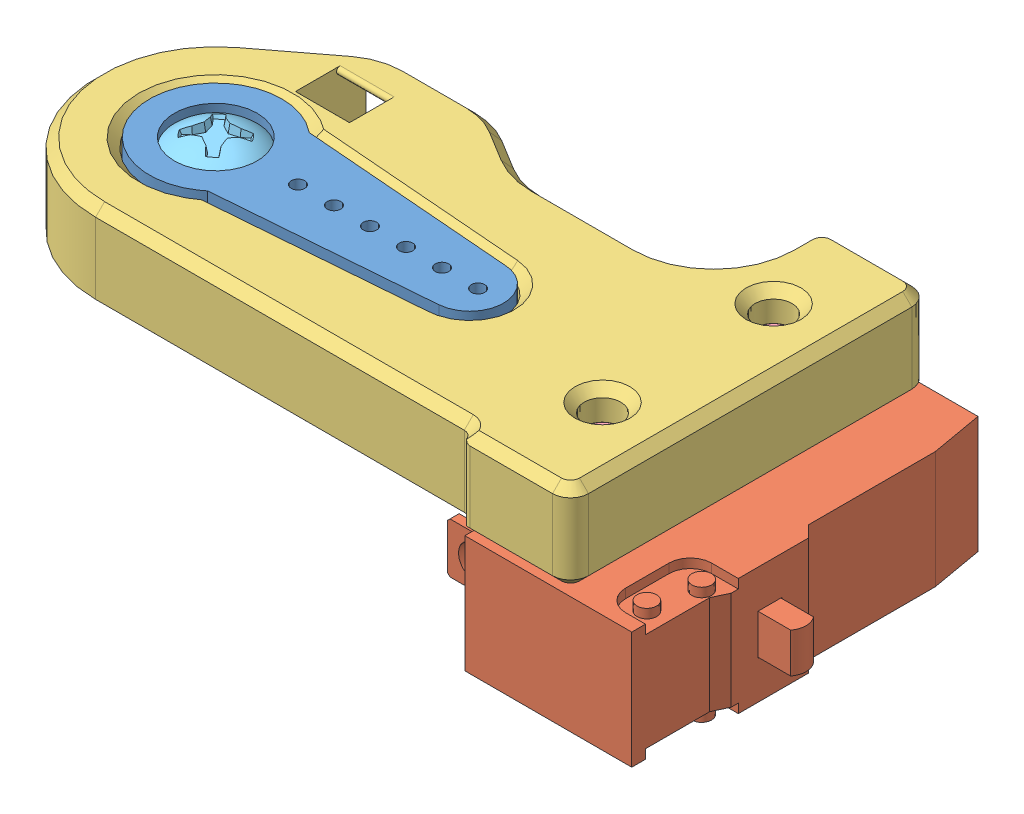
SolidWorks assembly ZProbeAssembly, configuration Default. Lengths in mm.
Overall size (39.46 14.76 19.99).
6 component instances, 5 part files, 12 mates.
Components (placement in the parent):
- Servo Horn-1: Servo Horn [Default] at (34.2536 11.8969 23.9402) size (19.66 4.12 7.35)
- SnapLimitSwitch-1: SnapLimitSwitch [Default] at (22.9628 5.2957 11.2222) x (0.000181 0 -1) z (0 -1 0) size (19.99 14.86 6.5)
- ZProbeArmMirrored-1: ZProbeArmMirrored [Default] at (-0.0025 17.1137 27.8606) x (1 0 0.000181) z (0.000181 0 -1) size (33.66 4.95 19.95)
- M2.5x10HexSocketScrew-1: M2.5x10HexSocketScrew [91292A014] at (25.3259 12.0445 6.4347) x (-0.001575 0 0.999999) z (0 1 0) size (4.5 4.5 13.01)
- M2.5x10HexSocketScrew-2: M2.5x10HexSocketScrew [91292A014] at (25.3241 12.0445 15.9347) x (-0.043466 0 0.999055) z (0 1 0) size (4.5 4.5 13.01)
- ServoScrew-1: ServoScrew [93406A071] at (1.841 12.5869 13.9305) x (0.770997 0 -0.636839) z (0 1 0) size (4.93 5.18 10.49)
Mates (geometry in assembly coordinates):
- Concentric1: concentric anti-aligned: cylinder of Servo Horn-1 through (1.841 13.5169 13.9305) axis (0 -1 0) radius 3.675; cylinder of ZProbeArmMirrored-1 through (1.841 11.8969 13.9305) axis (0 1 0) radius 3.775
- Coincident2: coincident anti-aligned: plane of Servo Horn-1 through (1.841 11.8969 13.9305) normal (0 -1 0); plane of ZProbeArmMirrored-1 through (1.841 11.8969 13.9305) normal (0 1 0)
- Concentric5: concentric aligned: circle of Servo Horn-1; circle of ZProbeArmMirrored-1
- Coincident3: coincident anti-aligned: plane of SnapLimitSwitch-1 through (22.9646 8.5469 1.2273) normal (0 1 0); plane of ZProbeArmMirrored-1 through (-0.0025 8.5469 27.8606) normal (0 -1 0)
- Concentric6: concentric aligned: cylinder of SnapLimitSwitch-1 through (25.3259 2.0445 6.4347) axis (0 1 0) radius 1.1049; cylinder of ZProbeArmMirrored-1 through (25.3259 8.5469 6.4347) axis (0 1 0) radius 1.025
- Parallel1: parallel anti-aligned: plane of SnapLimitSwitch-1 through (22.961 2.0445 21.2171) normal (-1 0 -0.000181); plane of ZProbeArmMirrored-1 through (28.822 8.5469 27.8658) normal (1 0 0.000181)
- Concentric42: concentric aligned: cylinder of ZProbeArmMirrored-1 through (25.3259 8.5469 6.4347) axis (0 1 0) radius 1.025; cylinder of M2.5x10HexSocketScrew-1 through (25.3259 -0.4555 6.4347) axis (0 1 0) radius 2.25
- Coincident95: coincident anti-aligned: plane of SnapLimitSwitch-1 through (22.9646 2.0445 1.2273) normal (0 -1 0); plane of M2.5x10HexSocketScrew-1 through (25.3259 2.0445 6.4347) normal (0 1 0)
- Concentric43: concentric aligned: cylinder of ZProbeArmMirrored-1 through (25.3241 8.5469 15.9347) axis (0 1 0) radius 1.025; cylinder of M2.5x10HexSocketScrew-2 through (25.3241 -0.4555 15.9347) axis (0 1 0) radius 2.25
- Coincident96: coincident anti-aligned: plane of SnapLimitSwitch-1 through (22.9646 2.0445 1.2273) normal (0 -1 0); plane of M2.5x10HexSocketScrew-2 through (25.3241 2.0445 15.9347) normal (0 1 0)
- Concentric44: concentric aligned: circle of Servo Horn-1; circle of ServoScrew-1
- Coincident97: coincident aligned: circle of Servo Horn-1; plane of ServoScrew-1 through (1.841 12.5869 13.9305) normal (0 -1 0)
